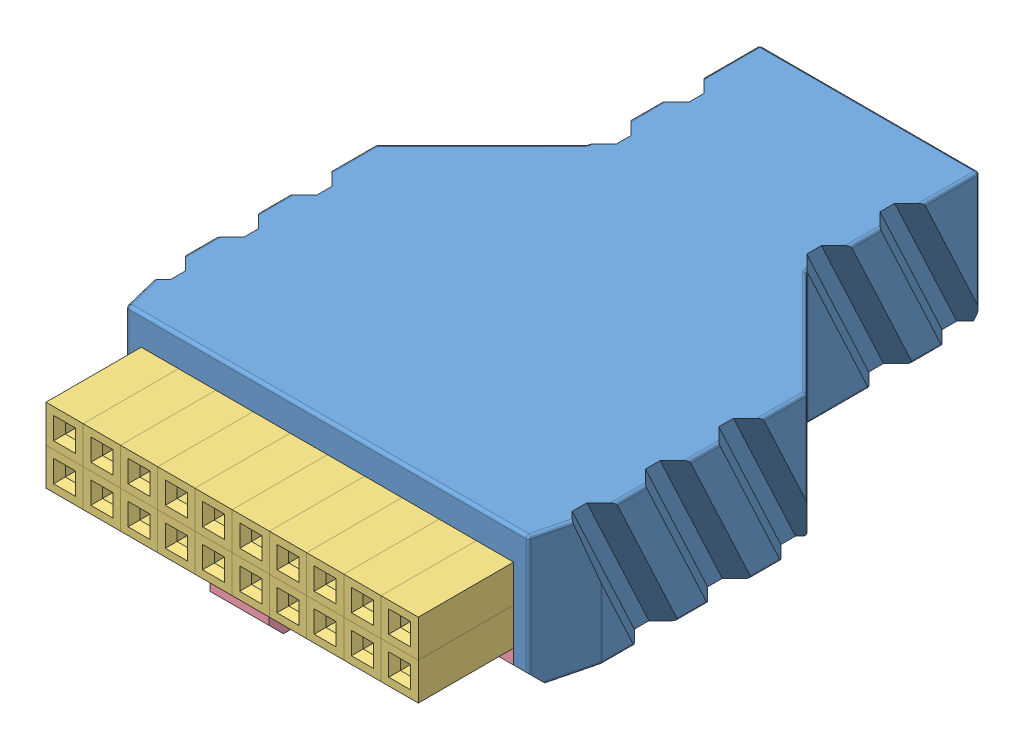
SolidWorks assembly ProgrammerConnector, configuration Programmer Connector. Lengths in mm.
Overall size (29.4 9.08 43.5).
5 component instances, 5 part files, 31 mates.
Components (placement in the parent):
- ProgrammerEnclosureBody^ProgrammerConnector-1: ProgrammerEnclosureBody^ProgrammerConnector [Programmer Enclosure Body] at (0 4.1 -35) x (0 0 -1) z (-1 0 0) size (37 9.08 29.4) (virtual)
- RoundCable^ProgrammerConnector-1: RoundCable^ProgrammerConnector [Default] at (-3.7974 -1.3 -49.3462) x (1 0 0) z (0 0 -1) size (12.39 3 25.83) (virtual)
- PBS-2 (DS-1023 - 2x10)-1: PBS-2 (DS-1023 - 2x10) [Connector PBS-2 (DS-1023 - 2x10)] at (11.43 -1.71 -37) x (0 1 0) z (1 0 0) size (5.08 11.5 25.4)
- ProgrammerEnclosureLid^ProgrammerConnector-1: ProgrammerEnclosureLid^ProgrammerConnector [Programmer Enclosure Lid] at (0 -2.98 -35) x (0 0 -1) z (-1 0 0) size (43 2 25.4) (virtual)
- Copy of BH-20R^ProgrammerConnector-1: Copy of BH-20R^ProgrammerConnector [Default] at (-16.443 3.8834 -25.9394) x (1 0 0) z (0 0 -1) (suppressed, hidden, virtual)
Mates (geometry in assembly coordinates):
- Coincident4: coincident aligned: plane of EnclosureLid^DeviceConnectorRound-1 through (0 -7.08 -35) normal (0 0 1); plane of Lid^cable-1 through (0 2.1 0.013) normal (0 0 1)
- Coincident5: coincident anti-aligned: plane of EnclosureLid^DeviceConnectorRound-1 through (0 -4.98 -70) normal (0 1 0); plane of Lid^cable-1 through (0 0.1 -27.487) normal (0 -1 0)
- Concentric1: concentric anti-aligned: cylinder of Self Tapping Cross recessed Screw 4Plastic^cable-1 through (-14 -8 -8.287) axis (0 -1 0) radius 0.78; cylinder of Lid^cable-1 through (-14 2.1 -8.287) axis (0 1 0) radius 1.5
- Coincident7: coincident aligned: cone of Self Tapping Cross recessed Screw 4Plastic^cable-1 through (-14 0.48 -8.287) axis (0 -1 0); cone of Lid^cable-1 through (-14 2.1 -8.287) axis (0 -1 0)
- Concentric2: concentric anti-aligned: cylinder of Self Tapping Cross recessed Screw 4Plastic^cable-2 through (14 -8 -8.287) axis (0 -1 0) radius 0.78; cylinder of Lid^cable-1 through (14 2.1 -8.287) axis (0 1 0) radius 1.5
- Coincident8: coincident aligned: cone of Self Tapping Cross recessed Screw 4Plastic^cable-2 through (14 0.48 -8.287) axis (0 -1 0); cone of Lid^cable-1 through (14 2.1 -8.287) axis (0 -1 0)
- Coincident10: coincident aligned: plane of board^cable-1 through (-0.9944 1 -14.4999) normal (0 1 0); plane of RibbonCable^DeviceConnector-1 through (0 0 -17.6612) normal (0 1 0)
- Coincident11: coincident anti-aligned: plane of board^cable-1 through (-0.9944 1 -14.4999) normal (0 1 0); plane of PBD-20-1 through (10.4356 1 0.5001) normal (0 -1 0)
- Coincident12: coincident anti-aligned: plane of board^cable-1 through (-13.8944 1.75 0.5001) normal (0 0 1); plane of PBD-20-1 through (9.1656 -1.54 0.5001) normal (0 0 -1)
- Coincident13: coincident anti-aligned: plane of EnclosureLid^DeviceConnectorRound-1 through (0 -9.08 -70) normal (1 0 0); plane of PBD-20-1 through (-0.9944 -0.27 0.5001) normal (-1 0 0)
- Coincident14: coincident anti-aligned: plane of RibbonCable^DeviceConnector-1 through (0 0 -17.6612) normal (1 0 0); plane of PBD-20-1 through (-0.9944 -0.27 0.5001) normal (-1 0 0)
- Coincident15: coincident anti-aligned: plane of EnclosureLid^DeviceConnectorRound-1 through (0 -6.03 -70) normal (0 1 0); plane of PBD-20-1 through (10.4356 1 0.5001) normal (0 -1 0)
- Coincident16: coincident aligned: plane of board^cable-1 through (-0.9944 1 -14.4999) normal (-1 0 0); plane of PBD-20-1 through (-0.9944 -0.27 0.5001) normal (-1 0 0)
- Concentric3: concentric anti-aligned: cylinder of board^cable-1 through (13.0056 0.25 -6.9999) axis (0 1 0) radius 3.4; cylinder of EnclosureBody^cable-1 through (5.0056 3.65 -8.287) axis (0 -1 0) radius 3.1
- Coincident17: coincident aligned: plane of EnclosureLid^DeviceConnectorRound-1 through (0 -9.08 -70) normal (1 0 0); plane of Lid^cable-1 through (0 0.1 -27.487) normal (1 0 0)
- Coincident18: coincident anti-aligned: plane of board^cable-1 through (-13.8944 1.75 0.5001) normal (0 0 1); plane of PLD2-NN (DS-1025-05 - 2xNN) 2mm^DeviceConnector-1 through (10 1.3335 -1.6) normal (0 0 -1)
- Coincident23: coincident anti-aligned: plane of EnclosureLid^DeviceConnectorRound-1 through (-5 -4.98 -70) normal (1 0 0); plane of PLD2-NN (DS-1025-05 - 2xNN) 2mm^DeviceConnector-1 through (-5 2 -2) normal (-1 0 0)
- Coincident24: coincident anti-aligned: plane of EnclosureLid^DeviceConnectorRound-1 through (0 -4.98 -70) normal (0 1 0); plane of ProgrammerEnclosureBody^ProgrammerConnector-1 through (0 -4.98 -35) normal (0 -1 0)
- Coincident25: coincident aligned: plane of RibbonCable^DeviceConnector-1 through (0 0 -17.6612) normal (1 0 0); plane of PLD2-NN (DS-1025-05 - 2xNN) 2mm^DeviceConnector-1 through (0 0 0) normal (1 0 0)
- Coincident26: coincident anti-aligned: plane of PLD2-NN (DS-1025-05 - 2xNN) 2mm^DeviceConnector-1 through (4 0 -2) normal (0 0 -1); plane of EnclosureBody^DeviceConnector-1 through (3.14 -1.9 -37) normal (0 0 1)
- Coincident28: coincident aligned: plane of RibbonCable^DeviceConnector-1 through (0 0 -17.6612) normal (0 1 0); plane of PLD2-NN (DS-1025-05 - 2xNN) 2mm^DeviceConnector-1 through (4 0 0) normal (0 1 0)
- Coincident29: coincident aligned: plane of EnclosureLid^DeviceConnectorRound-1 through (0 -7.08 -35) normal (0 0 1); plane of ProgrammerEnclosureBody^ProgrammerConnector-1 through (0 2.1 -35) normal (0 0 1)
- Coincident30: coincident anti-aligned: plane of PLD2-NN (DS-1025-05 - 2xNN) 2mm^DeviceConnector-1 through (4 0 0) normal (0 1 0); plane of ProgrammerEnclosureBody^ProgrammerConnector-1 through (0 -4.98 -35) normal (0 -1 0)
- Coincident31: coincident anti-aligned: plane of PLD2-NN (DS-1025-05 - 2xNN) 2mm^DeviceConnector-1 through (0 0 0) normal (1 0 0); plane of ProgrammerEnclosureBody^ProgrammerConnector-1 through (0 4.1 -35) normal (-1 0 0)
- Coincident32: coincident anti-aligned: plane of ProgrammerEnclosureBody^ProgrammerConnector-1 through (0 2.1 -35) normal (0 -1 0); plane of PBS-2 (DS-1023 - 1x2)-1 through (-12.7 2.1 -28.5) normal (0 1 0)
- Coincident33: coincident anti-aligned: plane of ProgrammerEnclosureBody^ProgrammerConnector-1 through (3.24 -1.9 -37) normal (0 0 1); plane of PBS-2 (DS-1023 - 1x2)-1 through (-1.27 0.83 -37) normal (0 0 -1)
- Coincident35: coincident aligned: plane of ProgrammerEnclosureBody^ProgrammerConnector-1 through (0 -4.98 -35) normal (0 -1 0); plane of ProgrammerEnclosureLid^ProgrammerConnector-1 through (0 -4.98 -35) normal (0 -1 0)
- Coincident36: coincident anti-aligned: plane of ProgrammerEnclosureBody^ProgrammerConnector-1 through (14.6 -4.98 -49.6) normal (-0.707107 0 0.707107); plane of ProgrammerEnclosureLid^ProgrammerConnector-1 through (14.6 -4.98 -49.6) normal (0.707107 0 -0.707107)
- Coincident37: coincident anti-aligned: plane of ProgrammerEnclosureBody^ProgrammerConnector-1 through (-14.6 -4.98 -49.6) normal (0.707107 0 0.707107); plane of ProgrammerEnclosureLid^ProgrammerConnector-1 through (-14.6 -4.98 -49.6) normal (-0.707107 0 -0.707107)
- Tangent1: tangent anti-aligned: plane of ProgrammerEnclosureBody^ProgrammerConnector-1 through (0 0.2 -35) normal (0 -1 0); cylinder of RoundCable^DeviceConnectorRound-1 through (0.0026 -1.3 -62.2194) axis (0 0 -1) radius 1.5
- Coincident38: coincident anti-aligned: plane of ProgrammerEnclosureBody^ProgrammerConnector-1 through (0 4.1 -35) normal (-1 0 0); plane of PBS-2 (DS-1023 - 1x2)-1 through (0 -1.71 -37) normal (1 0 0)
